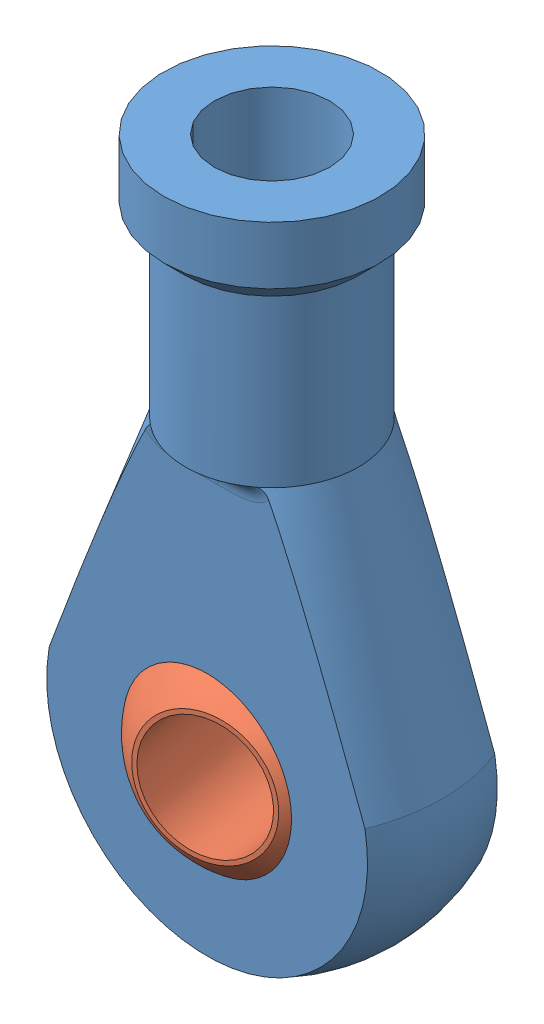
SolidWorks assembly ball_joint_assembly, configuration Default. Lengths in mm.
Overall size (24 48 15.04).
2 component instances, 2 part files, 1 mates.
Components (placement in the parent):
- pivot-1: pivot [Default] at (20.32 19.8016 39.1412) size (24 48 15)
- ball_joint_8mm-1: ball_joint_8mm [Default] at (20.32 19.8016 39.1412) x (0.959956 0.183636 -0.211569) z (0.205368 0.052377 0.977282) size (14.76 14.76 12)
Mates (geometry in assembly coordinates):
- Concentric1: concentric: sphere of pivot-1; sphere of ball_joint_8mm-1
